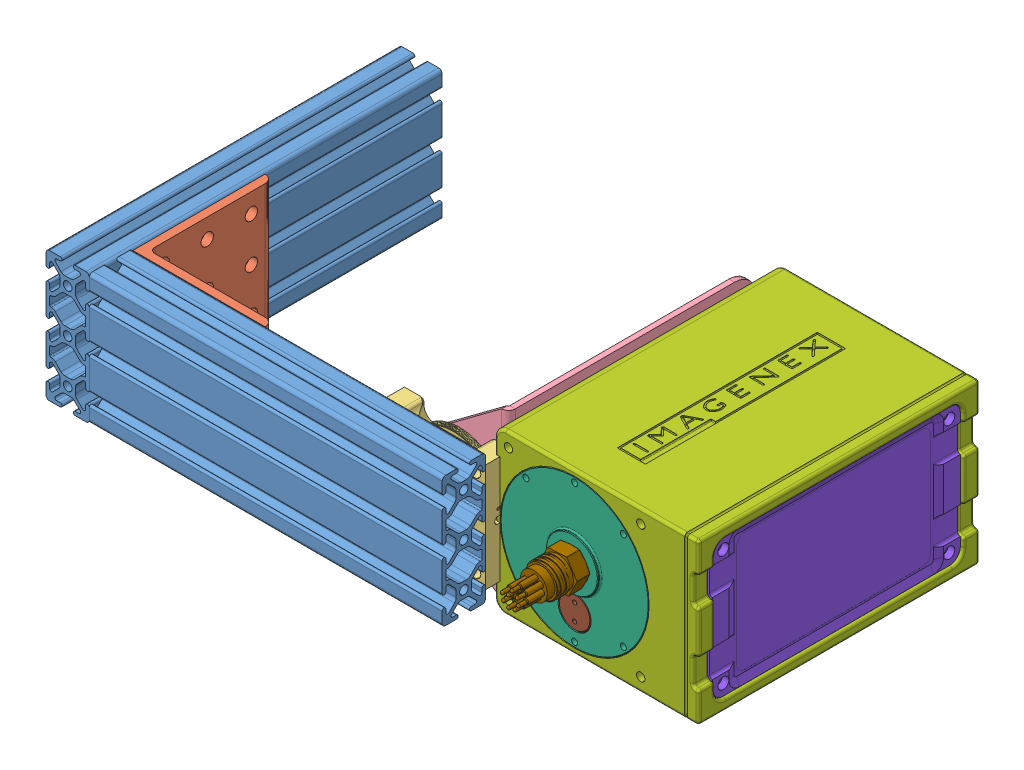
SolidWorks assembly aquatic_sensing, configuration Default. Lengths in mm.
Overall size (342.67 120.87 207.79).
13 component instances, 11 part files, 13 mates.
Components (placement in the parent):
- 25-2576-Black-203_2-CL-1: 25-2576-Black-203_2-CL [Default] at origin size (25 75 203.2)
- 25-2576-Black-203_2-CL-2: 25-2576-Black-203_2-CL [Default] at (12.5 0 -12.5) x (0 0 1) z (-1 0 0) size (25 75 203.2)
- 3136N177_T-Slotted Framing_Extended_Corner_Bracket_Triple_Rail-1: 3136N177_T-Slotted Framing_Extended_Corner_Bracket_Triple_Rail [3136N177] at (50.6 0 -63.1) x (1 0 0) z (0 1 0) size (76.2 76.2 73.03)
- rotation_mount_RP01M-1: rotation_mount_RP01M [Default] at (215.7 31.115 -40.494) x (0 -1 0) z (0 0 -1) size (62.23 62.23 16.13)
- sonar_mounting_clip-1: sonar_mounting_clip [Default] at (209.585 0 -114.154) x (-1 0 0) z (0 0 -1) size (50.8 95.25 142.88)
- DT100 Delrin-1: DT100 Delrin [Default] at (331.1367 -31.45 -119.3691) x (0 1 0) z (0 0 -1) size (120.87 131.81 199.71)
  - 325-717-01-MOD-1: 325-717-01-MOD [Default] at (31.45 -72.3392 61.4599) x (0 0 1) z (0.707107 0.707107 0) size (14.29 85.47 85.47)
  - 325-717-02-1: 325-717-02 [Default] at (31.45 -72.3392 -71.8901) x (0 0 -1) z (0.707107 0.707107 0) size (15.88 85.47 85.47)
  - d32571600-1: d32571600 [Default] at (77.4875 -29.5402 75.7474) size (92.08 117.41 161.93)
  - d33517700-1: d33517700 [Default] at (71.2645 -29.5402 66.2224) size (79.63 26.99 142.88)
  - subconnMCBH8MSS-1: subconnMCBH8MSS [Default] at (31.45 -72.3392 -87.7651) x (-0.837169 0.546944 0) z (-0.546944 -0.837169 0) size (21.88 48.89 20.68)
  - 325-601-00-1: 325-601-00 [Default] at (31.45 -72.3392 63.0474) x (1 0 0) z (0 -1 0) size (19.05 12.7 19.05)
  - 325-763-00-1: 325-763-00 [Default] at (6.685 -72.3392 -71.8901) x (1 0 0) z (0 1 0) size (19.05 14.29 19.05)
Mates (geometry in assembly coordinates):
- Width1: width anti-aligned: plane of 25-2576-Black-203_2-CL-1 through (-4.32 -37.5 0) normal (0 -1 0); plane of 3136N177_T-Slotted Framing_Extended_Corner_Bracket_Triple_Rail-1 through (-10.469 37.5 0) normal (0 1 0); plane of 25-2576-Black-203_2-CL-1 through (12.5 36.5125 -96.4248) normal (0 1 0); plane of 3136N177_T-Slotted Framing_Extended_Corner_Bracket_Triple_Rail-1 through (12.5 -36.5125 -96.4248) normal (0 -1 0)
- Coincident1: coincident anti-aligned: plane of 25-2576-Black-203_2-CL-1 through (12.5 20.68 0) normal (1 0 0); plane of 3136N177_T-Slotted Framing_Extended_Corner_Bracket_Triple_Rail-1 through (12.5 -36.5125 -101.2) normal (-1 0 0)
- Width2: width aligned: plane of 25-2576-Black-203_2-CL-2 through (12.5 37.5 -8.18) normal (0 1 0); plane of 25-2576-Black-203_2-CL-1 through (12.5 -37.5 -2.031) normal (0 -1 0); plane of 25-2576-Black-203_2-CL-2 through (4.32 37.5 0) normal (0 1 0); plane of 25-2576-Black-203_2-CL-1 through (10.469 -37.5 0) normal (0 -1 0)
- Coincident2: coincident aligned: plane of 25-2576-Black-203_2-CL-1 through (0 0 0) normal (0 0 1); plane of 25-2576-Black-203_2-CL-2 through (12.5 20.68 0) normal (0 0 1)
- Coincident3: coincident anti-aligned: plane of 25-2576-Black-203_2-CL-1 through (12.5 20.68 0) normal (1 0 0); plane of 25-2576-Black-203_2-CL-2 through (12.5 0 -12.5) normal (-1 0 0)
- Coincident4: coincident anti-aligned: plane of 25-2576-Black-203_2-CL-2 through (12.5 -20.68 -25) normal (0 0 -1); plane of 3136N177_T-Slotted Framing_Extended_Corner_Bracket_Triple_Rail-1 through (12.5 -36.5125 -25) normal (0 0 1)
- Coincident5: coincident anti-aligned: plane of 25-2576-Black-203_2-CL-2 through (12.5 4.32 -25) normal (0 0 -1); plane of rotation_mount_RP01M-1 through (184.585 0 -25) normal (0 0 1)
- Coincident6: coincident aligned: plane of 25-2576-Black-203_2-CL-2 through (215.7 0 -12.5) normal (1 0 0); plane of rotation_mount_RP01M-1 through (215.7 0 -40.494) normal (1 0 0)
- Width3: width anti-aligned: plane of 25-2576-Black-203_2-CL-2 through (12.5 37.5 -22.969) normal (0 1 0); plane of rotation_mount_RP01M-1 through (12.5 -37.5 -16.82) normal (0 -1 0); plane of 25-2576-Black-203_2-CL-2 through (184.585 -25.654 -40.494) normal (0 -1 0); plane of rotation_mount_RP01M-1 through (184.585 25.654 -40.494) normal (0 1 0)
- ProfileCenter1: profile center: circle of rotation_mount_RP01M-1; unknown of sonar_mounting_clip-1
- Concentric3: concentric anti-aligned: cylinder of rotation_mount_RP01M-1 through (197.085 0 -41.129) axis (0 0 -1) radius 2; cylinder of sonar_mounting_clip-1 through (197.085 0 -41.129) axis (0 0 1) radius 2.2479
- ProfileCenter3: profile center: unknown of DT100 Delrin-1/d32571600-1; unknown of sonar_mounting_clip-1
- Concentric4: concentric aligned: cylinder of sonar_mounting_clip-1 through (209.585 34.925 -57.004) axis (-1 0 0) radius 3.3782; cylinder of DT100 Delrin-1/d32571600-1 through (212.76 34.925 -57.004) axis (-1 0 0) radius 3.175
